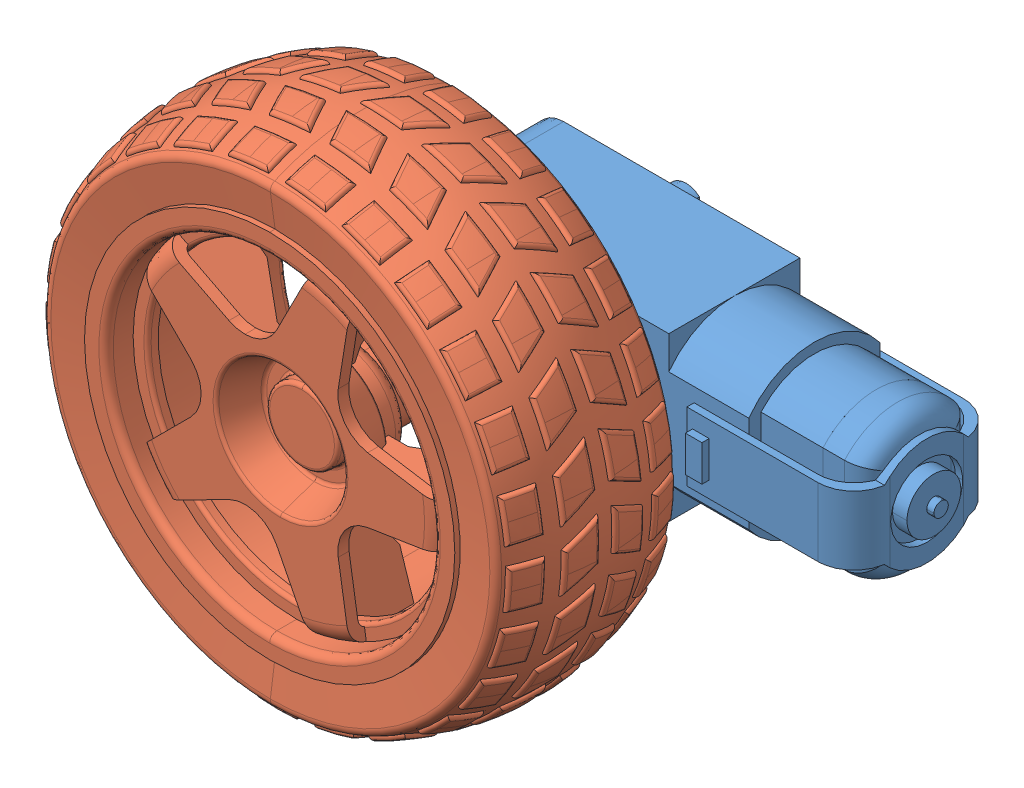
SolidWorks assembly Arduino_RC_CAR_01A.STEP, configuration Default. Lengths in mm.
Overall size (88.7 69.02 57.8).
74 component instances, 24 part files, 0 mates.
Components (placement in the parent):
- Assieme3^Macchina_2_sterzante.STEP-1: Assieme3^Macchina_2_sterzante.STEP [Default] at origin size (88.7 69.02 57.8)
  - Motor_Gear_Box_Standard.STEP-1: Motor_Gear_Box_Standard.STEP [Default] at (-91.71 -1.7 39) x (1 0 0) z (0 0 -1) size (70.5 22.6 37.6)
  - Wheel D65x25___ _________.STEP-1: Wheel D65x25___ _________.STEP [Default] at (-80.41 -13 87.1) x (0 -1 0) z (0 0 1) size (69.02 69.02 30)
- Assieme3^Macchina_2_sterzante.STEP-2: Assieme3^Macchina_2_sterzante.STEP [Default] at (0 -26 0) x (1 0 0) z (0 0 -1) size (88.7 69.02 57.8) (hidden)
  - Motor_Gear_Box_Standard.STEP-1: Motor_Gear_Box_Standard.STEP [Default] at (-91.71 -1.7 39) x (1 0 0) z (0 0 -1) size (70.5 22.6 37.6)
  - Wheel D65x25___ _________.STEP-1: Wheel D65x25___ _________.STEP [Default] at (-80.41 -13 87.1) x (0 -1 0) z (0 0 1) size (69.02 69.02 30)
- Ruota_ant_sterzante.STEP-1: Ruota_ant_sterzante.STEP [Default] at (70.3229 -13 70.9748) x (-0.890837 0 -0.454323) z (-0.454323 0 0.890837) size (74.19 74.2 40.2) (hidden)
  - mozzo1.STEP-1: mozzo1.STEP [Default] at origin size (26 24 27)
  - Semiasse1.STEP-1: Semiasse1.STEP [Default] at (0 0 -7) x (0.996952 -0.078016 0) z (0 0 1) size (12 12 12)
  - Wheel D65x25___ _________.STEP-1: Wheel D65x25___ _________.STEP [Default] at (0 0 13.2) x (0.996952 -0.078016 0) z (0 0 1) size (69.02 69.02 30)
- Ruota_ant_sterzante.STEP-2: Ruota_ant_sterzante.STEP [Default] at (90.2328 -13 -70.681) x (0.877042 0 0.480414) z (0.480414 0 -0.877042) size (74.19 74.2 40.2) (hidden)
  - mozzo1.STEP-1: mozzo1.STEP [Default] at origin size (26 24 27)
  - Semiasse1.STEP-1: Semiasse1.STEP [Default] at (0 0 -7) x (0.996952 -0.078016 0) z (0 0 1) size (12 12 12)
  - Wheel D65x25___ _________.STEP-1: Wheel D65x25___ _________.STEP [Default] at (0 0 13.2) x (0.996952 -0.078016 0) z (0 0 1) size (69.02 69.02 30)
- microservoAssembly.STEP-1: microservoAssembly.STEP [Default] at (77.0906 25.5655 26.0266) x (1 0 0) z (0 0 -1) size (32.3 29.8 12.41) (hidden)
  - microservoSG90.STEP-1: microservoSG90.STEP [Default] at (7.8094 3.3655 26.0766) size (32.3 29.8 12.41)
- Chassis2.STEP-1: Chassis2.STEP [Default] at origin size (192.71 4 120) (hidden)
- Ultrasonic HCSR04.STEP-1: Ultrasonic HCSR04.STEP [Default] at (108 -90.6627 49.1494) x (0 0 1) z (1 0 0) size (45 24.45 19.2) (hidden)
- 9V Battery Holder.STEP-1: 9V Battery Holder.STEP [Default] at (-77 2 27) x (0 -1 0) z (0 0 -1) size (30 20 54) (hidden)
- arduinoUno_Detailed.STEP-1: arduinoUno_Detailed.STEP [Default] at (10.5214 -26 2.03) x (0 0 1) z (-1 0 0) size (75.4 14.5 53.4) (hidden)
- L298N Motor Driver.STEP-1: L298N Motor Driver.STEP [Default] at (-55.25 0 0) x (0 0 -1) z (-1 0 0) size (43.5 26 43.5) (hidden)
- barra_sterzo3.STEP-1: barra_sterzo3.STEP [Default] at (89.0969 -13 -12.0753) x (0.904276 0 -0.426947) z (0.426947 0 0.904276) size (11.62 8.3 56.12) (hidden)
- microservoArm_A2.STEP-1: microservoArm_A2.STEP [Default] at (79.8 -9.1 -0.05) x (0.611636 0 -0.791139) z (0.791139 0 0.611636) size (34.4 3.9 7) (hidden)
- barra_sterzo3.STEP-2: barra_sterzo3.STEP [Default] at (70.5031 -13 11.9753) x (-0.898686 0 0.438592) z (-0.438592 0 -0.898686) size (11.62 8.3 56.12) (hidden)
- Copri_Chassis2.STEP-1: Copri_Chassis2.STEP [Default] at (0 -30 0) size (192.71 4 120) (hidden)
- perno_sterzo.STEP-1: perno_sterzo.STEP [Default] at (80 -1 -52) size (8 38.6 8) (hidden)
- spessore_sterzo.STEP-1: spessore_sterzo.STEP [Default] at (80 -25.8 -52) size (8 0.8 8) (hidden)
- mascherina.STEP-1: mascherina.STEP [Default] at (102 -26 22.5) x (0 0 -1) z (1 0 0) size (58 26 12.5) (hidden)
- colonnetta.STEP-1: colonnetta.STEP [Default] at (45 -26 27.5) size (13 26 13) (hidden)
- colonnetta.STEP-2: colonnetta.STEP [Default] at (45 -26 -27.5) size (13 26 13) (hidden)
- supporto_motore.STEP-1: supporto_motore.STEP [Default] at (-69 -26 -32) x (0 0 1) z (-1 0 0) size (14 30 21) (hidden)
- supporto_motore.STEP-2: supporto_motore.STEP [Default] at (-69 -26 32) x (0 0 1) z (-1 0 0) size (14 30 21) (hidden)
- perno_sterzo.STEP-2: perno_sterzo.STEP [Default] at (80 -1 52) size (8 38.6 8) (hidden)
- spessore_sterzo.STEP-2: spessore_sterzo.STEP [Default] at (80 -26 52) size (8 0.8 8) (hidden)
- seeger3.STEP-1: seeger3.STEP [Default] at (80 4.1 52) size (5 1.1 5.94) (hidden)
- seeger3.STEP-2: seeger3.STEP [Default] at (80 5.3 -52) x (-0.837169 0 -0.546944) z (-0.546944 0 0.837169) size (5 1.1 5.94) (hidden)
- seeger3.STEP-3: seeger3.STEP [Default] at (80 -30.1 52) x (-0.837169 0 -0.546944) z (-0.546944 0 0.837169) size (5 1.1 5.94) (hidden)
- seeger3.STEP-4: seeger3.STEP [Default] at (80 -30.1 -52) x (-0.837169 0 -0.546944) z (-0.546944 0 0.837169) size (5 1.1 5.94) (hidden)
- DIN7991_M4x35_ISO 7991 M04 x  20.STEP-1: DIN7991_M4x35_ISO 7991 M04 x  20.STEP [Default] at (102 4.3 -22.5) x (0 -1 0) z (0.040394 0 0.999184) size (37.3 8 8) (hidden)
- DIN7991_M4x35_ISO 7991 M04 x  20.STEP-2: DIN7991_M4x35_ISO 7991 M04 x  20.STEP [Default] at (102 4.3 22.5) x (0 -1 0) z (-0.992579 0 -0.121599) size (37.3 8 8) (hidden)
- M4 Nut.STEP-1: M4 Nut.STEP [Default] at (102 -30 -22.5) x (1 0 0) z (0 -1 0) size (8.1 8.09 3.22) (hidden)
- DIN7991_M4x35_ISO 7991 M04 x  20.STEP-3: DIN7991_M4x35_ISO 7991 M04 x  20.STEP [Default] at (45 4.3 -27.5) x (0 -1 0) z (-0.992579 0 -0.121599) size (37.3 8 8) (hidden)
- DIN7991_M4x35_ISO 7991 M04 x  20.STEP-4: DIN7991_M4x35_ISO 7991 M04 x  20.STEP [Default] at (-69 4.3 -32) x (0 -1 0) z (-0.992579 0 -0.121599) size (37.3 8 8) (hidden)
- DIN7991_M4x35_ISO 7991 M04 x  20.STEP-5: DIN7991_M4x35_ISO 7991 M04 x  20.STEP [Default] at (-69 4.3 32) x (0 -1 0) z (-0.992579 0 -0.121599) size (37.3 8 8) (hidden)
- DIN7991_M4x35_ISO 7991 M04 x  20.STEP-6: DIN7991_M4x35_ISO 7991 M04 x  20.STEP [Default] at (45 4.3 27.5) x (0 -1 0) z (-0.992579 0 -0.121599) size (37.3 8 8) (hidden)
- M4 Nut.STEP-2: M4 Nut.STEP [Default] at (102 -30 22.5) x (1 0 0) z (0 -1 0) size (8.1 8.09 3.22) (hidden)
- M4 Nut.STEP-3: M4 Nut.STEP [Default] at (-69 -30 -32) x (0.920165 0 0.391532) z (0 -1 0) size (8.1 8.09 3.22) (hidden)
- M4 Nut.STEP-4: M4 Nut.STEP [Default] at (45 -30 27.5) x (1 0 0.000614) z (0 -1 0) size (8.1 8.09 3.22) (hidden)
- M4 Nut.STEP-5: M4 Nut.STEP [Default] at (45 -30 -27.5) x (0.998478 0 0.055145) z (0 -1 0) size (8.1 8.09 3.22) (hidden)
- M4 Nut.STEP-6: M4 Nut.STEP [Default] at (-69 -30 32) x (0.949732 0 0.313063) z (0 -1 0) size (8.1 8.09 3.22) (hidden)
- DIN_EN_ISO_7380_M3x8.ipt.STEP-1: DIN_EN_ISO_7380_M3x8.ipt.STEP [Default] at (19.3514 -24.5 35.06) x (-0.613574 0 0.789637) z (0 1 0) size (6.44 6.44 9.5) (hidden)
- DIN_EN_ISO_7380_M3x8.ipt.STEP-2: DIN_EN_ISO_7380_M3x8.ipt.STEP [Default] at (-36.5 4 18.75) x (0.99735 0 0.072756) z (0 1 0) size (6.44 6.44 9.5) (hidden)
- DIN_EN_ISO_7380_M3x8.ipt.STEP-3: DIN_EN_ISO_7380_M3x8.ipt.STEP [Default] at (-8.8186 -24.5 35.06) x (0.998471 0 -0.055271) z (0 1 0) size (6.44 6.44 9.5) (hidden)
- DIN_EN_ISO_7380_M3x8.ipt.STEP-4: DIN_EN_ISO_7380_M3x8.ipt.STEP [Default] at (-74 4 -18.75) x (0.999981 0 -0.00624) z (0 1 0) size (6.44 6.44 9.5) (hidden)
- DIN_EN_ISO_7380_M3x8.ipt.STEP-5: DIN_EN_ISO_7380_M3x8.ipt.STEP [Default] at (-36.5 4 -18.75) x (0.998879 0 0.047332) z (0 1 0) size (6.44 6.44 9.5) (hidden)
- DIN_EN_ISO_7380_M3x8.ipt.STEP-6: DIN_EN_ISO_7380_M3x8.ipt.STEP [Default] at (-74 4 18.75) x (0.933529 0 0.358501) z (0 1 0) size (6.44 6.44 9.5) (hidden)
- M3 Nut.STEP-1: M3 Nut.STEP [Default] at (-13.6386 -30 -17) x (1 0 0) z (0 -1 0) size (6.36 6.36 2.41) (hidden)
- M3 Nut.STEP-2: M3 Nut.STEP [Default] at (-8.8186 -32.4 35.06) x (-0.690778 0 0.723067) z (0 1 0) size (6.36 6.36 2.41) (hidden)
- M3 Nut.STEP-3: M3 Nut.STEP [Default] at (34.6814 -30 -15.75) x (1 0 0) z (0 -1 0) size (6.36 6.36 2.41) (hidden)
- M3 Nut.STEP-4: M3 Nut.STEP [Default] at (19.3514 -32.4 35.06) x (1 0 0) z (0 1 0) size (6.36 6.36 2.41) (hidden)
- DIN_EN_ISO_7380_M3x8.ipt.STEP-7: DIN_EN_ISO_7380_M3x8.ipt.STEP [Default] at (-13.6386 -24.5 -17) x (-0.613574 0 0.789637) z (0 1 0) size (6.44 6.44 9.5) (hidden)
- DIN_EN_ISO_7380_M3x8.ipt.STEP-8: DIN_EN_ISO_7380_M3x8.ipt.STEP [Default] at (34.6814 -24.5 -15.75) x (0.904734 0 -0.425977) z (0 1 0) size (6.44 6.44 9.5) (hidden)
- M3 Nut.STEP-5: M3 Nut.STEP [Default] at (-74 -1.5 -18.75) x (0.964342 0 -0.264661) z (0 -1 0) size (6.36 6.36 2.41) (hidden)
- M3 Nut.STEP-6: M3 Nut.STEP [Default] at (-36.5 -1.5 -18.75) x (1 0 0) z (0 -1 0) size (6.36 6.36 2.41) (hidden)
- M3 Nut.STEP-7: M3 Nut.STEP [Default] at (-74 -1.5 18.75) x (0.994576 0 -0.104011) z (0 -1 0) size (6.36 6.36 2.41) (hidden)
- M3 Nut.STEP-8: M3 Nut.STEP [Default] at (-36.5 -1.5 18.75) x (1 0 0) z (0 -1 0) size (6.36 6.36 2.41) (hidden)
- ISO 7380_M3x35_ISO 7380 - M3 x 10.STEP-1: ISO 7380_M3x35_ISO 7380 - M3 x 10.STEP [Default] at (-59.91 -4 -58.85) x (0 0 1) z (-0.999411 0.034306 0) size (36.65 5.7 5.7) (hidden)
- ISO 7380_M3x35_ISO 7380 - M3 x 10.STEP-2: ISO 7380_M3x35_ISO 7380 - M3 x 10.STEP [Default] at (-59.91 -22 58.85) x (0 0 -1) z (0.958742 0.284277 0) size (36.65 5.7 5.7) (hidden)
- ISO 7380_M3x35_ISO 7380 - M3 x 10.STEP-3: ISO 7380_M3x35_ISO 7380 - M3 x 10.STEP [Default] at (-59.91 -4 58.85) x (0 0 -1) z (0.983256 0.182229 0) size (36.65 5.7 5.7) (hidden)
- ISO 7380_M3x35_ISO 7380 - M3 x 10.STEP-4: ISO 7380_M3x35_ISO 7380 - M3 x 10.STEP [Default] at (-59.91 -22 -58.85) x (0 0 1) z (-0.742875 0.66943 0) size (36.65 5.7 5.7) (hidden)
- M3 Nut.STEP-9: M3 Nut.STEP [Default] at (-59.91 -22 25) x (1 0 0) z (0 0 -1) size (6.36 6.36 2.41) (hidden)
- M3 Nut.STEP-10: M3 Nut.STEP [Default] at (-59.91 -22 -25) x (0.995162 0.098253 0) z (0 0 1) size (6.36 6.36 2.41) (hidden)
- M3 Nut.STEP-11: M3 Nut.STEP [Default] at (-59.91 -4 25) x (1 0 0) z (0 0 -1) size (6.36 6.36 2.41) (hidden)
- M3 Nut.STEP-12: M3 Nut.STEP [Default] at (-59.91 -4 -25) x (0.94863 -0.316387 0) z (0 0 1) size (6.36 6.36 2.41) (hidden)
